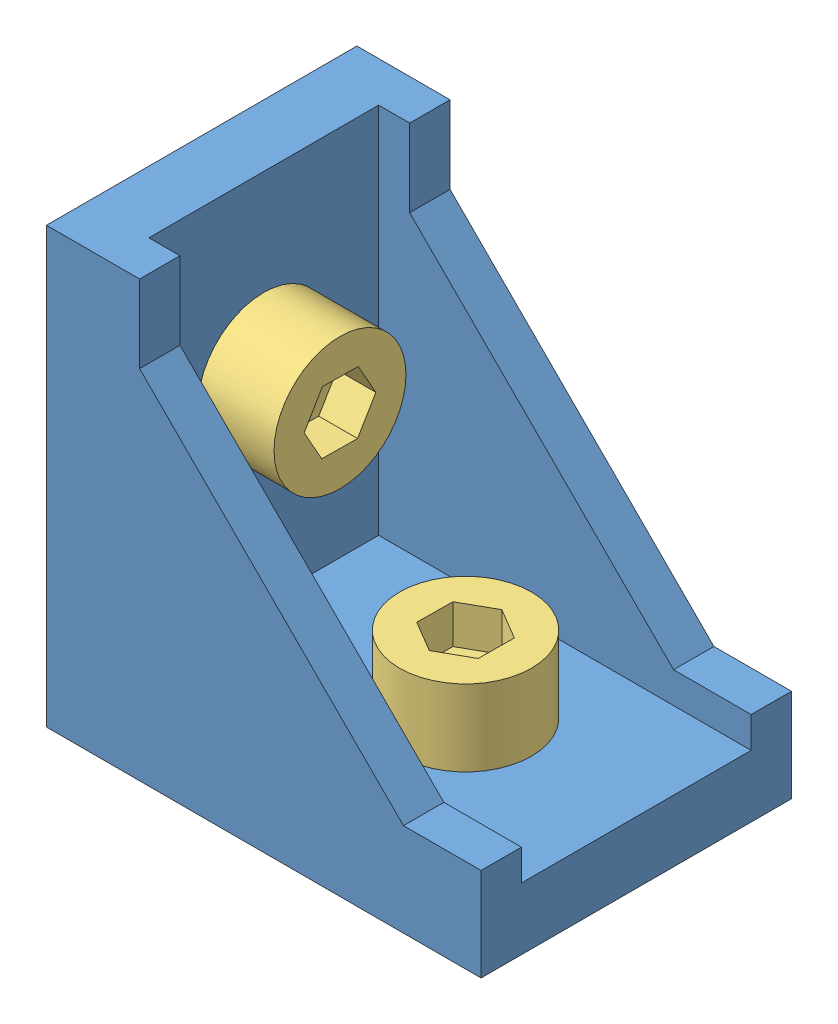
SolidWorks assembly 20角件加螺丝, configuration 默认. Lengths in mm.
Overall size (34 34 20).
5 component instances, 3 part files, 8 mates.
Components (placement in the parent):
- 角件20-1: 角件20 [默认] at (-16.321 -12.0491 19.5) size (29.5 29.5 20)
- 欧标20M5T形螺母-1: 欧标20M5T形螺母 [默认] at (3.679 -18.0491 34.5) x (0 0 -1) z (1 0 0) size (10 4.5 6)
- M5_8-1: M5_8 [默认] at (0.679 -16.0491 29.5) size (8.5 12.91 8.5)
- 欧标20M5T形螺母-2: 欧标20M5T形螺母 [默认] at (-22.321 1.9509 34.5) x (0 0 -1) z (0 -1 0) size (10 4.5 6)
- M5_8-2: M5_8 [默认] at (-20.321 4.9509 29.5) x (0 -1 0) z (0 0 1) size (8.5 12.91 8.5)
Mates (geometry in assembly coordinates):
- 重合1: coincident: plane of assembly; plane of assembly; plane of 角件20-1 through (-16.321 -13.5491 19.5) normal (0 -1 0); plane of 欧标20M5T形螺母-1 through (0.679 -13.5491 29.5) normal (0 1 0)
- 同心1: concentric: cylinder of assembly; cylinder of assembly; cylinder of 角件20-1 through (0.679 15.9519 29.5) axis (0 -1 0) radius 3; cylinder of 欧标20M5T形螺母-1 through (0.679 -14.7491 29.5) axis (0 -1 0) radius 2.5
- 同心2: concentric: cylinder of assembly; cylinder of assembly; cylinder of 角件20-1 through (0.679 15.9519 29.5) axis (0 -1 0) radius 3; cylinder of M5_8-1 through (0.679 -8.0491 29.5) axis (0 -1 0) radius 2.5
- 重合2: coincident: plane of assembly; plane of assembly; plane of 角件20-1 through (11.679 -8.0491 39.5) normal (0 1 0); plane of M5_8-1 through (0.679 -8.0491 29.5) normal (0 -1 0)
- 重合3: coincident: plane of assembly; plane of assembly; plane of 角件20-1 through (-17.821 -12.0491 19.5) normal (-1 0 0); plane of 欧标20M5T形螺母-2 through (-17.821 4.9509 29.5) normal (1 0 0)
- 同心3: concentric: cylinder of assembly; cylinder of assembly; cylinder of 角件20-1 through (11.68 4.9509 29.5) axis (-1 0 0) radius 3; cylinder of 欧标20M5T形螺母-2 through (-19.021 4.9509 29.5) axis (-1 0 0) radius 2.5
- 同心4: concentric: cylinder of assembly; cylinder of assembly; cylinder of 角件20-1 through (11.68 4.9509 29.5) axis (-1 0 0) radius 3; cylinder of M5_8-2 through (-12.321 4.9509 29.5) axis (-1 0 0) radius 2.5
- 重合4: coincident: plane of assembly; plane of assembly; plane of 角件20-1 through (-12.321 15.9509 39.5) normal (1 0 0); plane of M5_8-2 through (-12.321 4.9509 29.5) normal (-1 0 0)
